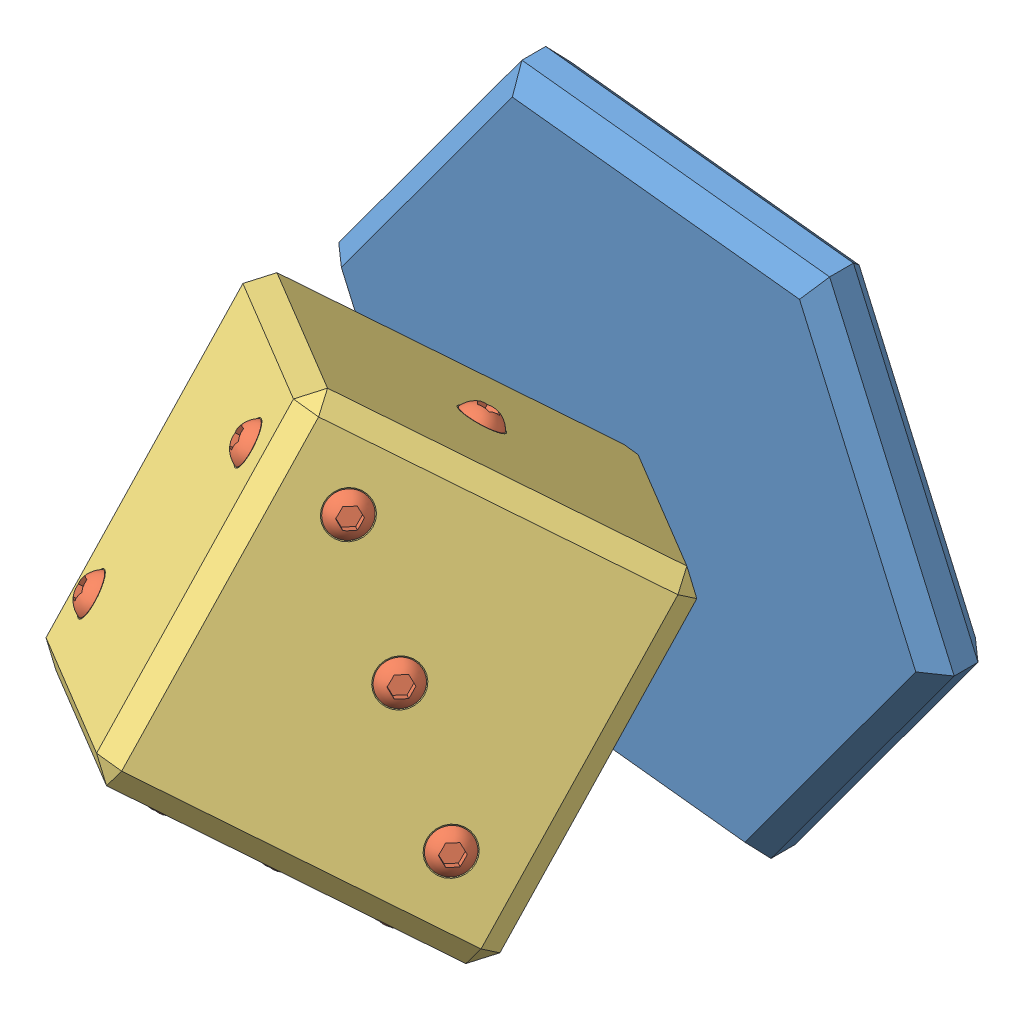
SolidWorks assembly würfel, configuration Standard. Lengths in mm.
Overall size (103.3 95.14 100.8).
24 component instances, 3 part files, 44 mates.
Components (placement in the parent):
- fuß-1: fuß [Standard] at (-11.5704 6.2235 0) size (103.3 95.14 10)
- schraube-1: schraube [Standard] at (-12.0559 2.17 82.9008) x (-0.935912 0.271713 0.224146) z (-0.09709 -0.810704 0.57735) size (6.4 6.4 8.67)
- schraube-2: schraube [Standard] at (-35.3256 -7.7894 65.003) x (0.592058 0.419246 0.688259) z (-0.09709 -0.810704 0.57735) size (6.4 6.4 8.67)
- schraube-3: schraube [Standard] at (-11.8284 33.8025 65.003) x (0.619383 0.78425 0.036297) z (-0.653545 0.489434 0.57735) size (6.4 6.4 8.67)
- schraube-4: schraube [Standard] at (12.4426 -7.3426 65.003) x (0.289618 0.625412 -0.724556) z (0.750635 0.321269 0.57735) size (6.4 6.4 8.67)
- schraube-5: schraube [Standard] at (-4.8075 32.9617 65.003) x (0.289618 0.625412 -0.724556) z (0.750635 0.321269 0.57735) size (6.4 6.4 8.67)
- schraube-6: schraube [Standard] at (3.8176 12.8095 65.003) x (0.289618 0.625412 -0.724556) z (0.750635 0.321269 0.57735) size (6.4 6.4 8.67)
- schraube-7: schraube [Standard] at (11.9572 -11.3961 59.2295) x (-0.493429 -0.853925 0.165345) z (0.653545 -0.489434 -0.57735) size (6.4 6.4 8.67)
- schraube-8: schraube [Standard] at (14.967 13.7357 41.3316) x (-0.493429 -0.853925 0.165345) z (0.653545 -0.489434 -0.57735) size (6.4 6.4 8.67)
- schraube-9: schraube [Standard] at (-11.3125 -21.3555 41.3316) x (-0.493429 -0.853925 0.165345) z (0.653545 -0.489434 -0.57735) size (6.4 6.4 8.67)
- schraube-10: schraube [Standard] at (1.8272 -3.8099 41.3316) x (-0.493429 -0.853925 0.165345) z (0.653545 -0.489434 -0.57735) size (6.4 6.4 8.67)
- schraube-11: schraube [Standard] at (-8.3027 3.7763 23.4338) x (-0.493429 -0.853925 0.165345) z (0.653545 -0.489434 -0.57735) size (6.4 6.4 8.67)
- schraube-12: schraube [Standard] at (8.204 -13.0025 65.003) x (-0.994948 0.093945 -0.0354) z (-0.09709 -0.810704 0.57735) size (6.4 6.4 8.67)
- schraube-13: schraube [Standard] at (-1.926 -5.4163 73.9519) x (-0.109098 0.585264 0.80347) z (-0.09709 -0.810704 0.57735) size (6.4 6.4 8.67)
- schraube-14: schraube [Standard] at (-11.085 10.2772 77.1272) x (-0.994948 0.093945 -0.0354) z (-0.09709 -0.810704 0.57735) size (6.4 6.4 8.67)
- schraube-15: schraube [Standard] at (-15.0657 -22.9618 47.1051) x (0.24417 -0.581765 -0.775842) z (-0.09709 -0.810704 0.57735) size (6.4 6.4 8.67)
- schraube-16: schraube [Standard] at (-9.5801 22.8429 41.3316) x (0.994859 -0.06226 0.079877) z (0.09709 0.810704 -0.57735) size (6.4 6.4 8.67)
- schraube-17: schraube [Standard] at (-25.1956 -15.3756 56.054) x (-0.509005 -0.458044 -0.728773) z (-0.09709 -0.810704 0.57735) size (6.4 6.4 8.67)
- schraube-18: schraube [Standard] at (-18.3334 -20.5147 41.3316) x (0.627542 -0.073254 -0.775129) z (-0.750635 -0.321269 -0.57735) size (6.4 6.4 8.67)
- schraube-19: schraube [Standard] at (-38.5933 -5.3422 59.2295) x (0.627542 -0.073254 -0.775129) z (-0.750635 -0.321269 -0.57735) size (6.4 6.4 8.67)
- schraube-20: schraube [Standard] at (-15.3236 4.6172 23.4338) x (0.627542 -0.073254 -0.775129) z (-0.750635 -0.321269 -0.57735) size (6.4 6.4 8.67)
- schraube-21: schraube [Standard] at (-35.5835 19.7896 41.3316) x (0.627542 -0.073254 -0.775129) z (-0.750635 -0.321269 -0.57735) size (6.4 6.4 8.67)
- würfel-1: würfel [Standard] at (9.072 15.0584 69.0444) x (-0.653545 0.489434 0.57735) z (-0.750635 -0.321269 -0.57735) size (55.43 55.43 55)
- schraube-23: schraube [Standard] at (-38.1078 -1.2887 65.003) x (0.619383 0.78425 0.036297) z (-0.653545 0.489434 0.57735) size (6.4 6.4 8.67)
Mates (geometry in assembly coordinates):
- Deckungsgleich1: coincident anti-aligned: circle of fuß-1 centre (-11.5704 6.2235 10) axis (0 0 1); circle of würfel-1 centre (-11.5704 6.2235 10) axis (0 0 -1)
- Konzentrisch1: concentric aligned: circle of würfel-1 centre (7.6855 -17.3316 68.086) axis (-0.09709 -0.810704 0.57735); circle of schraube-12 centre (7.7185 -17.056 67.8897) axis (-0.09709 -0.810704 0.57735)
- Deckungsgleich2: coincident aligned: plane of würfel-1 through (-16.9104 -38.3652 37.2902) normal (-0.09709 -0.810704 0.57735); circle of schraube-12 centre (7.5244 -18.6774 69.0444) axis (-0.09709 -0.810704 0.57735)
- Konzentrisch2: concentric aligned: circle of würfel-1 centre (-2.4444 -9.7454 77.035) axis (-0.09709 -0.810704 0.57735); circle of schraube-13 centre (-2.4114 -9.4698 76.8387) axis (-0.09709 -0.810704 0.57735)
- Konzentrisch3: concentric aligned: circle of würfel-1 centre (-12.5744 -2.1592 85.9839) axis (-0.09709 -0.810704 0.57735); circle of schraube-14 centre (-11.5704 6.2237 80.0139) axis (-0.09709 -0.810704 0.57735)
- Konzentrisch4: concentric aligned: circle of würfel-1 centre (-15.5841 -27.291 50.1882) axis (-0.09709 -0.810704 0.57735); circle of schraube-15 centre (-15.5511 -27.0153 49.9919) axis (-0.09709 -0.810704 0.57735)
- Konzentrisch5: concentric aligned: circle of würfel-1 centre (-25.7141 -19.7048 59.1371) axis (-0.09709 -0.810704 0.57735); circle of schraube-17 centre (-25.6811 -19.4291 58.9408) axis (-0.09709 -0.810704 0.57735)
- Deckungsgleich3: coincident aligned: circle of schraube-15 centre (-15.7453 -28.6368 51.1466) axis (-0.09709 -0.810704 0.57735); plane of würfel-1 through (-16.9104 -38.3652 37.2902) normal (-0.09709 -0.810704 0.57735)
- Deckungsgleich5: coincident aligned: circle of schraube-13 centre (-2.6056 -11.0912 77.9934) axis (-0.09709 -0.810704 0.57735); plane of würfel-1 through (-16.9104 -38.3652 37.2902) normal (-0.09709 -0.810704 0.57735)
- Deckungsgleich6: coincident aligned: circle of schraube-17 centre (-25.8753 -21.0505 60.0955) axis (-0.09709 -0.810704 0.57735); plane of würfel-1 through (-16.9104 -38.3652 37.2902) normal (-0.09709 -0.810704 0.57735)
- Konzentrisch6: concentric aligned: circle of schraube-1 centre (-12.5413 -1.8835 85.7876) axis (-0.09709 -0.810704 0.57735); circle of würfel-1 centre (-12.5744 -2.1592 85.9839) axis (-0.09709 -0.810704 0.57735)
- Konzentrisch7: concentric aligned: circle of schraube-2 centre (-35.811 -11.8429 67.8897) axis (-0.09709 -0.810704 0.57735); circle of würfel-1 centre (-35.844 -12.1185 68.086) axis (-0.09709 -0.810704 0.57735)
- Deckungsgleich7: coincident aligned: circle of schraube-2 centre (-36.0052 -13.4643 69.0444) axis (-0.09709 -0.810704 0.57735); plane of würfel-1 through (-16.9104 -38.3652 37.2902) normal (-0.09709 -0.810704 0.57735)
- Deckungsgleich9: coincident aligned: circle of schraube-1 centre (-12.7355 -3.5049 86.9423) axis (-0.09709 -0.810704 0.57735); plane of würfel-1 through (-16.9104 -38.3652 37.2902) normal (-0.09709 -0.810704 0.57735)
- Konzentrisch8: concentric aligned: circle of schraube-7 centre (15.2249 -13.8433 56.3427) axis (0.653545 -0.489434 -0.57735); circle of würfel-1 centre (15.4471 -14.0097 56.1464) axis (0.653545 -0.489434 -0.57735)
- Konzentrisch9: concentric aligned: circle of schraube-8 centre (18.2347 11.2885 38.4449) axis (0.653545 -0.489434 -0.57735); circle of würfel-1 centre (18.4569 11.1221 38.2486) axis (0.653545 -0.489434 -0.57735)
- Konzentrisch10: concentric aligned: circle of schraube-10 centre (5.0949 -6.2571 38.4449) axis (0.653545 -0.489434 -0.57735); circle of würfel-1 centre (5.3172 -6.4235 38.2486) axis (0.653545 -0.489434 -0.57735)
- Konzentrisch11: concentric aligned: circle of schraube-9 centre (-8.0448 -23.8027 38.4449) axis (0.653545 -0.489434 -0.57735); circle of würfel-1 centre (-7.8226 -23.9691 38.2486) axis (0.653545 -0.489434 -0.57735)
- Konzentrisch12: concentric aligned: circle of schraube-11 centre (-5.035 1.3292 20.547) axis (0.653545 -0.489434 -0.57735); circle of würfel-1 centre (-4.8128 1.1627 20.3507) axis (0.653545 -0.489434 -0.57735)
- Deckungsgleich10: coincident aligned: circle of schraube-7 centre (16.532 -14.8222 55.188) axis (0.653545 -0.489434 -0.57735); plane of würfel-1 through (-11.5704 6.2235 5.5359) normal (0.653545 -0.489434 -0.57735)
- Deckungsgleich11: coincident aligned: circle of schraube-8 centre (19.5418 10.3096 37.2902) axis (0.653545 -0.489434 -0.57735); plane of würfel-1 through (-11.5704 6.2235 5.5359) normal (0.653545 -0.489434 -0.57735)
- Deckungsgleich12: coincident aligned: circle of schraube-10 centre (6.402 -7.2359 37.2902) axis (0.653545 -0.489434 -0.57735); plane of würfel-1 through (-11.5704 6.2235 5.5359) normal (0.653545 -0.489434 -0.57735)
- Deckungsgleich13: coincident aligned: circle of schraube-9 centre (-6.7377 -24.7815 37.2902) axis (0.653545 -0.489434 -0.57735); plane of würfel-1 through (-11.5704 6.2235 5.5359) normal (0.653545 -0.489434 -0.57735)
- Deckungsgleich14: coincident aligned: circle of schraube-11 centre (-3.7279 0.3503 19.3923) axis (0.653545 -0.489434 -0.57735); plane of würfel-1 through (-11.5704 6.2235 5.5359) normal (0.653545 -0.489434 -0.57735)
- Konzentrisch13: concentric aligned: circle of schraube-18 centre (-22.0866 -22.121 38.4449) axis (-0.750635 -0.321269 -0.57735); circle of würfel-1 centre (-22.3418 -22.2302 38.2486) axis (-0.750635 -0.321269 -0.57735)
- Konzentrisch14: concentric aligned: circle of schraube-19 centre (-42.3465 -6.9485 56.3427) axis (-0.750635 -0.321269 -0.57735); circle of würfel-1 centre (-42.6017 -7.0578 56.1464) axis (-0.750635 -0.321269 -0.57735)
- Konzentrisch15: concentric aligned: circle of schraube-21 centre (-39.3367 18.1833 38.4449) axis (-0.750635 -0.321269 -0.57735); circle of würfel-1 centre (-39.5919 18.074 38.2486) axis (-0.750635 -0.321269 -0.57735)
- Konzentrisch16: concentric aligned: circle of schraube-20 centre (-19.0768 3.0108 20.547) axis (-0.750635 -0.321269 -0.57735); circle of würfel-1 centre (-19.332 2.9016 20.3507) axis (-0.750635 -0.321269 -0.57735)
- Deckungsgleich15: coincident aligned: circle of schraube-20 centre (-20.5781 2.3683 19.3923) axis (-0.750635 -0.321269 -0.57735); plane of würfel-1 through (-16.9104 -38.3652 37.2902) normal (-0.750635 -0.321269 -0.57735)
- Deckungsgleich16: coincident aligned: circle of schraube-21 centre (-40.838 17.5407 37.2902) axis (-0.750635 -0.321269 -0.57735); plane of würfel-1 through (-16.9104 -38.3652 37.2902) normal (-0.750635 -0.321269 -0.57735)
- Deckungsgleich17: coincident aligned: circle of schraube-18 centre (-23.5879 -22.7635 37.2902) axis (-0.750635 -0.321269 -0.57735); plane of würfel-1 through (-16.9104 -38.3652 37.2902) normal (-0.750635 -0.321269 -0.57735)
- Deckungsgleich18: coincident aligned: circle of schraube-19 centre (-43.8477 -7.5911 55.188) axis (-0.750635 -0.321269 -0.57735); plane of würfel-1 through (-16.9104 -38.3652 37.2902) normal (-0.750635 -0.321269 -0.57735)
- Konzentrisch17: concentric aligned: circle of schraube-6 centre (7.5707 14.4159 67.8897) axis (0.750635 0.321269 0.57735); circle of würfel-1 centre (7.826 14.5251 68.086) axis (0.750635 0.321269 0.57735)
- Konzentrisch18: concentric aligned: circle of schraube-5 centre (-1.0543 34.568 67.8897) axis (0.750635 0.321269 0.57735); circle of würfel-1 centre (-0.7991 34.6772 68.086) axis (0.750635 0.321269 0.57735)
- Konzentrisch20: concentric aligned: circle of schraube-4 centre (16.1958 -5.7363 67.8897) axis (0.750635 0.321269 0.57735); circle of würfel-1 centre (16.451 -5.627 68.086) axis (0.750635 0.321269 0.57735)
- Deckungsgleich19: coincident aligned: circle of schraube-4 centre (17.6971 -5.0937 69.0444) axis (0.750635 0.321269 0.57735); plane of würfel-1 through (24.3745 -20.6954 69.0444) normal (0.750635 0.321269 0.57735)
- Deckungsgleich20: coincident aligned: circle of schraube-6 centre (9.072 15.0584 69.0444) axis (0.750635 0.321269 0.57735); plane of würfel-1 through (24.3745 -20.6954 69.0444) normal (0.750635 0.321269 0.57735)
- Deckungsgleich21: coincident aligned: circle of schraube-5 centre (0.447 35.2105 69.0444) axis (0.750635 0.321269 0.57735); plane of würfel-1 through (24.3745 -20.6954 69.0444) normal (0.750635 0.321269 0.57735)
- Konzentrisch22: concentric aligned: circle of schraube-16 centre (-9.0946 26.8964 38.4449) axis (0.09709 0.810704 -0.57735); circle of würfel-1 centre (-9.0616 27.1721 38.2486) axis (0.09709 0.810704 -0.57735)
- Deckungsgleich22: coincident aligned: circle of schraube-16 centre (-8.9005 28.5178 37.2902) axis (0.09709 0.810704 -0.57735); plane of würfel-1 through (-11.5704 6.2235 5.5359) normal (0.09709 0.810704 -0.57735)
- Konzentrisch25: concentric aligned: circle of schraube-3 centre (-15.0961 36.2496 67.8897) axis (-0.653545 0.489434 0.57735); circle of würfel-1 centre (-15.3183 36.4161 68.086) axis (-0.653545 0.489434 0.57735)
- Deckungsgleich23: coincident aligned: circle of schraube-3 centre (-16.4032 37.2285 69.0444) axis (-0.653545 0.489434 0.57735); plane of würfel-1 through (-47.5154 33.1424 37.2902) normal (-0.653545 0.489434 0.57735)
- Konzentrisch26: concentric aligned: circle of würfel-1 centre (-41.5978 1.3249 68.086) axis (-0.653545 0.489434 0.57735); circle of schraube-23 centre (-41.3756 1.1585 67.8897) axis (-0.653545 0.489434 0.57735)
- Deckungsgleich24: coincident aligned: plane of würfel-1 through (-47.5154 33.1424 37.2902) normal (-0.653545 0.489434 0.57735); circle of schraube-23 centre (-42.6827 2.1374 69.0444) axis (-0.653545 0.489434 0.57735)
